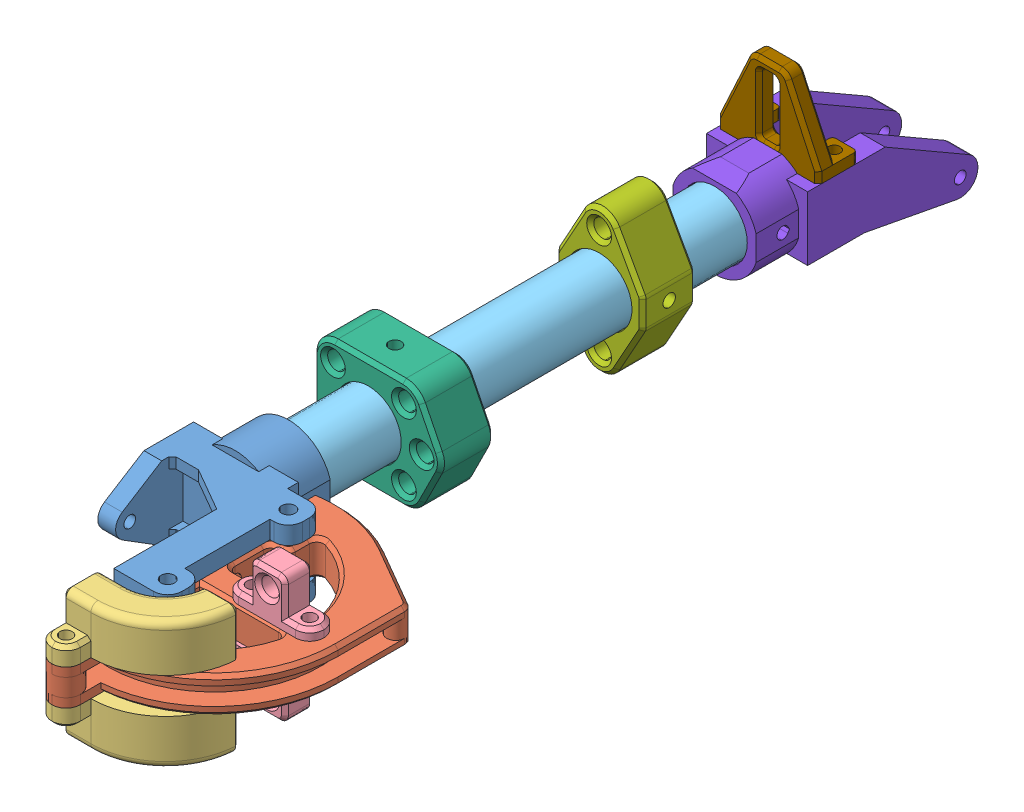
SolidWorks assembly link_leg_l, configuration ﾃﾞﾌｫﾙﾄ. Lengths in mm.
Overall size (70.45 52.25 265.64).
11 component instances, 9 part files, 26 mates.
Components (placement in the parent):
- shoulder_joint_connector-1: shoulder_joint_connector [outer] at origin size (39.7 24.5 59)
- shoulder_joint_circle-1: shoulder_joint_circle [ﾃﾞﾌｫﾙﾄ] at (19.95 5 26) x (1 0 0) z (0 -1 0) size (40 79.64 10)
- shoulder_fromknee_middle_curve-1: shoulder_fromknee_middle_curve [mirror] at (18.95 5 58.641) x (0 0 1) z (0 1 0) size (28 28.97 13)
- shoulder_fromknee_middle_curve-2: shoulder_fromknee_middle_curve [ﾃﾞﾌｫﾙﾄ] at (18.95 -5 58.641) x (0 0 1) z (0 1 0) size (28 28.97 13)
- shoulder_fromknee_middle-1: shoulder_fromknee_middle [ﾃﾞﾌｫﾙﾄ] at (38.95 5 26) x (1 0 0) z (0 -1 0) size (24 8 13)
- shoulder_fromknee_middle-2: shoulder_fromknee_middle [ﾃﾞﾌｫﾙﾄ] at (38.95 -5 26) x (-1 0 0) z (0 1 0) size (24 8 13)
- pipe_leg-1: pipe_leg [ﾃﾞﾌｫﾙﾄ] x (1 0 0) z (0 0 -1) size (18 18 150)
- wire_end_5_small-1: wire_end_5_small [ﾃﾞﾌｫﾙﾄ] at (0 0 -45) x (0 -1 0) z (0 0 1) size (31 35.94 15)
- wire_end_small-1: wire_end_small [ﾃﾞﾌｫﾙﾄ] at (0 0 -110) x (0 1 0) z (0 0 1) size (40.5 24.5 15)
- knee2-1: knee2 [outer] at (0 0 -135) x (1 0 0) z (0 0 -1) size (28.5 25.58 60)
- knee_support-1: knee_support [ﾃﾞﾌｫﾙﾄ] at (0 9 -158) x (1 0 0) z (0 1 0) size (28.5 11 23)
Mates (geometry in assembly coordinates):
- 同心円2: concentric aligned: cylinder of shoulder_joint_connector-1 through (19.95 10.35 5) axis (0 -1 0) radius 1.9; cylinder of shoulder_joint_circle-1 through (19.95 5 5) axis (0 -1 0) radius 1.75
- 同心円3: concentric aligned: cylinder of shoulder_joint_connector-1 through (19.95 10.35 39) axis (0 -1 0) radius 1.9; cylinder of shoulder_joint_circle-1 through (19.95 5 39) axis (0 -1 0) radius 1.75
- 幅1: width anti-aligned: plane of shoulder_joint_connector-1 through (24.95 -5.35 0) normal (0 1 0); plane of shoulder_joint_connector-1 through (24.95 5.35 0) normal (0 -1 0); plane of shoulder_joint_circle-1 through (19.95 -5 26) normal (0 -1 0); plane of shoulder_joint_circle-1 through (19.95 5 26) normal (0 1 0)
- 同心円5: concentric anti-aligned: cylinder of shoulder_joint_circle-1 through (18.95 -2.5 66.641) axis (0 -1 0) radius 1.75; cylinder of shoulder_fromknee_middle_curve-1 through (18.95 5 66.641) axis (0 1 0) radius 1.75
- 同心円6: concentric anti-aligned: cylinder of shoulder_joint_circle-1 through (18.95 5 50.641) axis (0 -1 0) radius 1.75; cylinder of shoulder_fromknee_middle_curve-1 through (18.95 5 50.641) axis (0 1 0) radius 1.75
- 一致1: coincident anti-aligned: plane of shoulder_joint_circle-1 through (19.95 5 26) normal (0 1 0); plane of shoulder_fromknee_middle_curve-1 through (22.95 5 46.641) normal (0 -1 0)
- 同心円7: concentric aligned: cylinder of shoulder_joint_circle-1 through (18.95 -2.5 66.641) axis (0 -1 0) radius 1.75; cylinder of shoulder_fromknee_middle_curve-2 through (18.95 -5 66.641) axis (0 -1 0) radius 1.75
- 同心円8: concentric aligned: cylinder of shoulder_joint_circle-1 through (18.95 5 50.641) axis (0 -1 0) radius 1.75; cylinder of shoulder_fromknee_middle_curve-2 through (18.95 -5 50.641) axis (0 -1 0) radius 1.75
- 一致2: coincident anti-aligned: plane of shoulder_joint_circle-1 through (19.95 -5 26) normal (0 -1 0); plane of shoulder_fromknee_middle_curve-2 through (22.95 -5 46.641) normal (0 1 0)
- 同心円9: concentric anti-aligned: cylinder of shoulder_joint_circle-1 through (46.95 5 26) axis (0 -1 0) radius 1.75; cylinder of shoulder_fromknee_middle-1 through (46.95 5 26) axis (0 1 0) radius 1.75
- 同心円10: concentric anti-aligned: cylinder of shoulder_joint_circle-1 through (30.95 5 26) axis (0 -1 0) radius 1.75; cylinder of shoulder_fromknee_middle-1 through (30.95 5 26) axis (0 1 0) radius 1.75
- 一致3: coincident anti-aligned: plane of shoulder_joint_circle-1 through (19.95 5 26) normal (0 1 0); plane of shoulder_fromknee_middle-1 through (26.95 5 30) normal (0 -1 0)
- 同心円11: concentric aligned: cylinder of shoulder_joint_circle-1 through (30.95 5 26) axis (0 -1 0) radius 1.75; cylinder of shoulder_fromknee_middle-2 through (30.95 -5 26) axis (0 -1 0) radius 1.75
- 同心円12: concentric aligned: cylinder of shoulder_joint_circle-1 through (46.95 5 26) axis (0 -1 0) radius 1.75; cylinder of shoulder_fromknee_middle-2 through (46.95 -5 26) axis (0 -1 0) radius 1.75
- 一致4: coincident anti-aligned: plane of shoulder_joint_circle-1 through (19.95 -5 26) normal (0 -1 0); plane of shoulder_fromknee_middle-2 through (50.95 -5 30) normal (0 1 0)
- 同心円15: concentric anti-aligned: cylinder of pipe_leg-1 through (0 0 -150) axis (0 0 1) radius 9; cylinder of wire_end_5_small-1 through (0 0 -37.5) axis (0 0 -1) radius 9.25
- 同心円16: concentric aligned: cylinder of pipe_leg-1 through (0 9 -45) axis (0 -1 0) radius 1.75; cylinder of wire_end_5_small-1 through (0 15.5 -45) axis (0 -1 0) radius 1.75
- 同心円17: concentric anti-aligned: cylinder of pipe_leg-1 through (0 0 -150) axis (0 0 1) radius 9; cylinder of wire_end_small-1 through (0 0 -102.5) axis (0 0 -1) radius 9.25
- 同心円18: concentric anti-aligned: cylinder of pipe_leg-1 through (-9 0 -110) axis (1 0 0) radius 1.75; cylinder of wire_end_small-1 through (12.25 0 -110) axis (-1 0 0) radius 1.75
- 一致5: coincident anti-aligned: plane of knee2-1 through (-14.25 9 -153) normal (0 1 0); plane of knee_support-1 through (0 9 -158) normal (0 -1 0)
- 同心円21: concentric aligned: cylinder of knee2-1 through (-10.75 9 -158) axis (0 -1 0) radius 1.8; cylinder of knee_support-1 through (-10.75 12 -158) axis (0 -1 0) radius 1.65
- 同心円22: concentric aligned: cylinder of knee2-1 through (10.75 9 -158) axis (0 -1 0) radius 1.8; cylinder of knee_support-1 through (10.75 12 -158) axis (0 -1 0) radius 1.65
- 同心円23: concentric aligned: cylinder of shoulder_joint_connector-1 through (-14.75 0 -7.5) axis (1 0 0) radius 1.65; cylinder of pipe_leg-1 through (-9 0 -7.5) axis (1 0 0) radius 1.75
- 同心円24: concentric aligned: cylinder of shoulder_joint_connector-1 through (0 0 -15) axis (0 0 1) radius 9.25; cylinder of pipe_leg-1 through (0 0 -150) axis (0 0 1) radius 9
- 同心円25: concentric aligned: cylinder of pipe_leg-1 through (-9 0 -142.5) axis (1 0 0) radius 1.75; cylinder of knee2-1 through (-14.25 0 -142.5) axis (1 0 0) radius 1.65
- 同心円26: concentric anti-aligned: cylinder of pipe_leg-1 through (0 0 -150) axis (0 0 1) radius 9; cylinder of knee2-1 through (0 0 -135) axis (0 0 -1) radius 9.25
